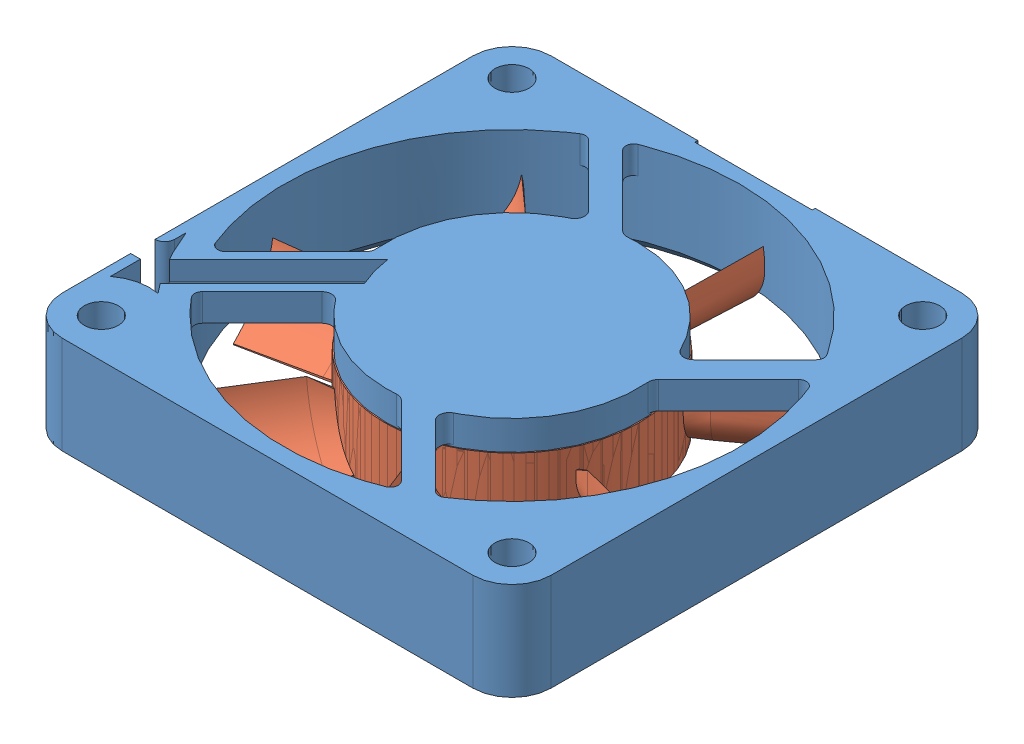
SolidWorks assembly fan_asm, configuration Default. Lengths in mm.
Overall size (54.48 10.28 54.48).
2 component instances, 2 part files, 0 mates.
Components (placement in the parent):
- fan_case-1: fan_case [Default] at origin size (50 10.1 50)
- fan-1: fan [Default] at (415.4421 3.5826 -113.9746) x (0.605351 0 0.795959) z (0.795959 0 -0.605351) size (45.4 7.28 44.65)
